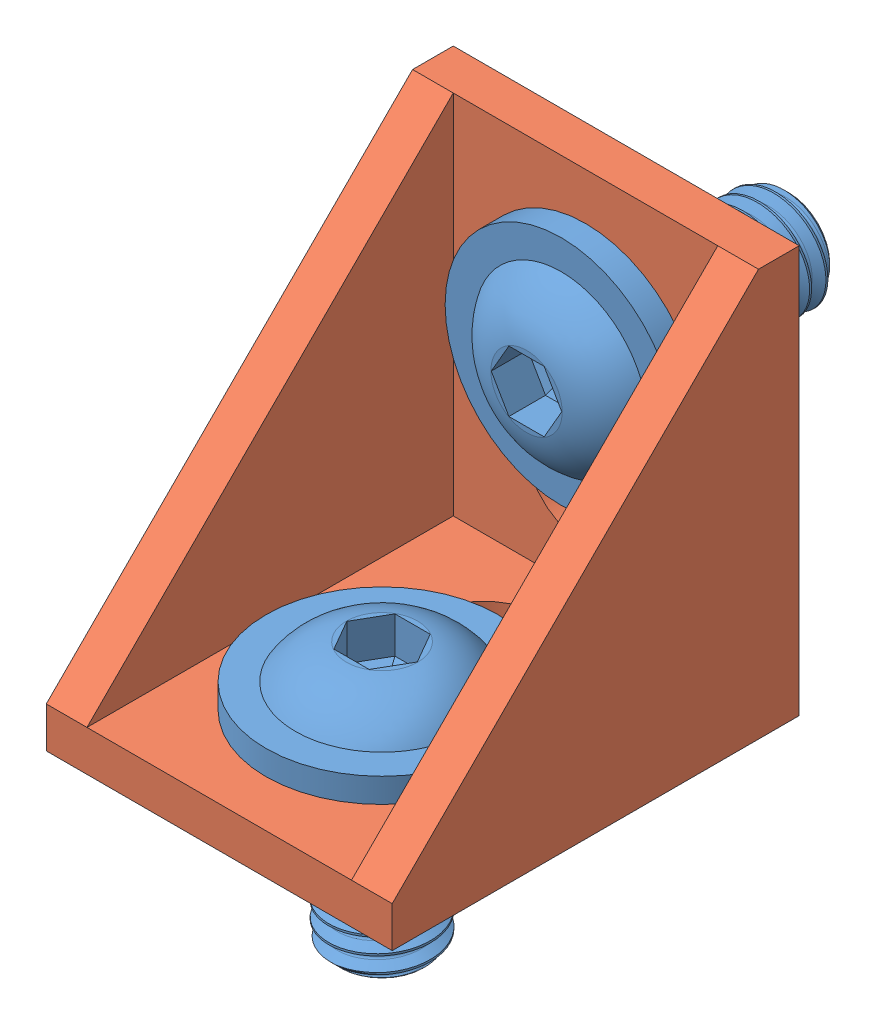
SolidWorks assembly LClamp, configuration Default. Lengths in mm.
Overall size (17 28.23 28.23).
3 component instances, 2 part files, 4 mates.
Components (placement in the parent):
- Lens flange screw M5x20-1: Lens flange screw M5x20 [Standard] at (4.7729 6.3642 6.7454) size (11.4 11.4 13.13)
- RS-CCB-2017-5 [Cast Aluminum Corner Bracket]-1: RS-CCB-2017-5 [Cast Aluminum Corner Bracket] [RS-CCB-2017-5] at (4.7729 4.3642 4.7454) size (17 21 21)
- Lens flange screw M5x20-2: Lens flange screw M5x20 [Standard] at (4.7729 -3.6358 16.7454) x (1 0 0) z (0 1 0) size (11.4 11.4 13.13)
Mates (geometry in assembly coordinates):
- Coincident1: coincident anti-aligned: plane of Lens flange screw M5x20-1 through (4.7729 6.3642 6.7454) normal (0 0 -1); plane of RS-CCB-2017-5 [Cast Aluminum Corner Bracket]-1 through (-1.7271 -3.6358 6.7454) normal (0 0 1)
- Concentric1: concentric aligned: cylinder of Lens flange screw M5x20-1 through (4.7729 6.3642 -3.2546) axis (0 0 1) radius 2.5; cylinder of RS-CCB-2017-5 [Cast Aluminum Corner Bracket]-1 through (4.7729 6.3642 4.7444) axis (0 0 1) radius 3
- Coincident2: coincident anti-aligned: plane of RS-CCB-2017-5 [Cast Aluminum Corner Bracket]-1 through (4.7729 -3.6358 4.7454) normal (0 1 0); plane of Lens flange screw M5x20-2 through (4.7729 -3.6358 16.7454) normal (0 -1 0)
- Concentric2: concentric anti-aligned: cylinder of RS-CCB-2017-5 [Cast Aluminum Corner Bracket]-1 through (4.7729 -5.6368 16.7454) axis (0 1 0) radius 3; cylinder of Lens flange screw M5x20-2 through (4.7729 -2.4358 16.7454) axis (0 -1 0) radius 5.7
